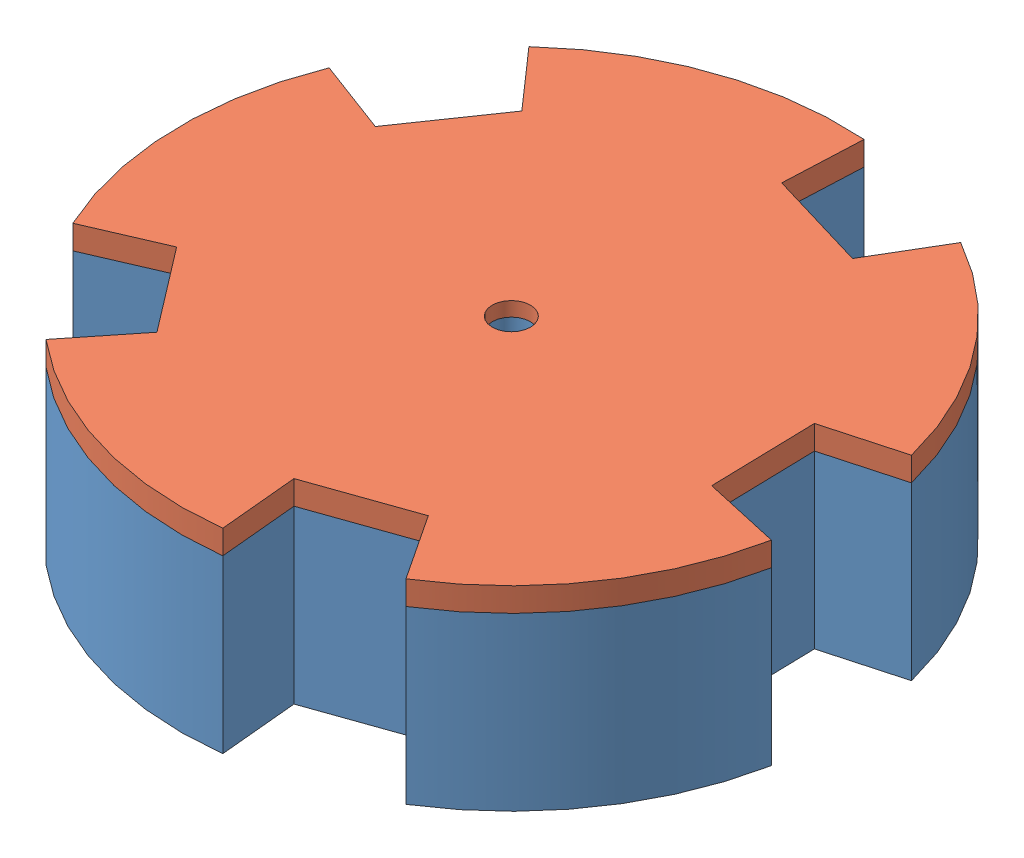
SolidWorks assembly neoprene_wheel_cutting_asm, configuration Default. Lengths in mm.
Overall size (68.35 21.4 69).
2 component instances, 2 part files, 4 mates.
Components (placement in the parent):
- neoprene_wheel-1: neoprene_wheel [Default] at (20.8131 41.0447 52.1497) size (68.35 19.9 69)
- neoprene_wheel_cutting_tool-1: neoprene_wheel_cutting_tool [Default] at (20.8131 50.9947 52.1497) x (1 0 0) z (0 1 0) size (68.35 69 2.5)
Mates (geometry in assembly coordinates):
- InPlace1: in place: plane of neoprene_wheel-1 through (20.8131 50.9947 52.1497) normal (0 1 0); plane of ? through (0 50.9947 0) normal (0 1 0); moOrthogonalPlaneRef_w of neoprene_wheel-1 through (20.8131 50.9947 52.1497) normal (0 1 0); plane of ? through (0 50.9947 0) normal (0 0 -1); plane of neoprene_wheel-1 through (20.8131 50.9947 52.1497) normal (0 1 0); plane of ? through (0 50.9947 0) normal (1 0 0); plane of neoprene_wheel-1 through (20.8131 50.9947 52.1497) normal (0 1 0); unknown of neoprene_wheel_cutting_tool-1
- Coincident1: coincident aligned: plane of neoprene_wheel-1; plane of neoprene_wheel_cutting_tool-1
- Coincident2: coincident aligned: moOrthogonalPlaneRef_w of neoprene_wheel-1 through (20.8131 50.9947 52.1497) normal (0 0 -1); plane of neoprene_wheel_cutting_tool-1 through (20.8131 50.9947 52.1497) normal (0 0 -1)
- Coincident3: coincident anti-aligned: moOrthogonalPlaneRef_w of neoprene_wheel-1 through (20.8131 50.9947 52.1497) normal (-1 0 0); plane of neoprene_wheel_cutting_tool-1 through (20.8131 50.9947 52.1497) normal (1 0 0)
